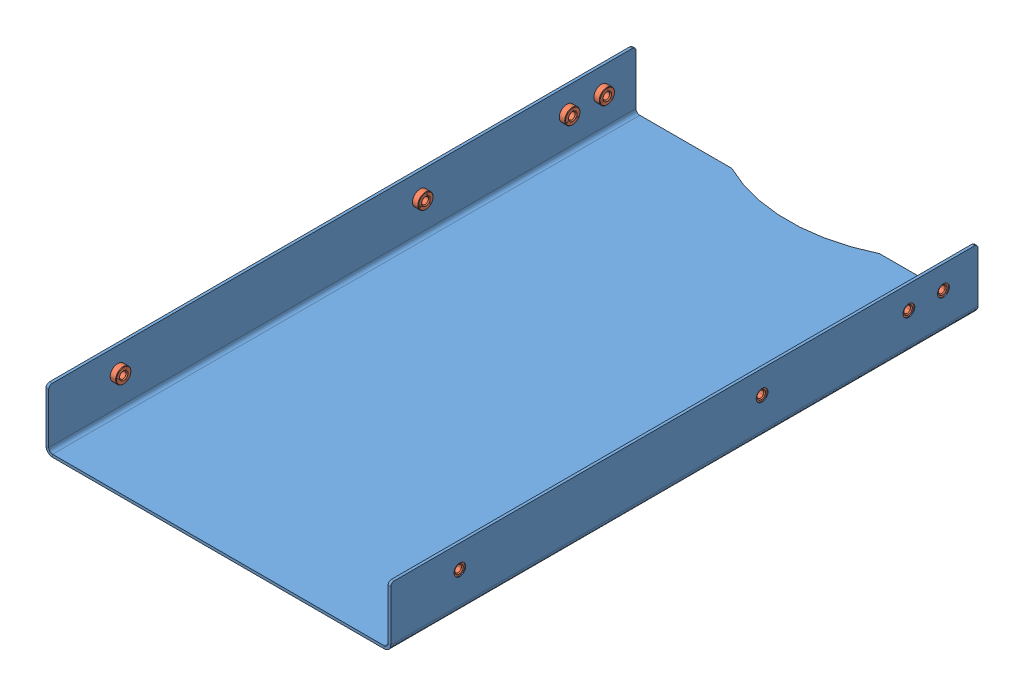
SolidWorks assembly GE-22334, configuration Default. Lengths in mm.
Overall size (253.49 44.45 431.8).
9 component instances, 2 part files, 22 mates.
Components (placement in the parent):
- GE-22334-01-1: GE-22334-01 [Default] at origin size (253.49 44.45 431.8)
- pem_clinchnut_.25_20_.054-1: pem_clinchnut_.25_20_.054 [Default] at (0.6223 25.4 -50.8) size (5.69 11.18 11.18)
- pem_clinchnut_.25_20_.054-6: pem_clinchnut_.25_20_.054 [Default] at (0.6223 25.4 -406.4) x (1 0 0) z (0 -0.371154 0.928571) size (5.69 11.18 11.18)
- pem_clinchnut_.25_20_.054-8: pem_clinchnut_.25_20_.054 [Default] at (252.8697 25.4 -406.4) x (-1 0 0) z (0 -0.421154 -0.906989) size (5.69 11.18 11.18)
- pem_clinchnut_.25_20_.054-14: pem_clinchnut_.25_20_.054 [Default] at (252.8697 25.4 -50.8) x (-1 0 0) z (0 -0.305088 -0.952324) size (5.69 11.18 11.18)
- pem_clinchnut_.25_20_.054-16: pem_clinchnut_.25_20_.054 [Default] at (0.6223 25.4 -273.05) x (1 0 0) z (0 -0.313094 0.949722) size (5.69 11.18 11.18)
- pem_clinchnut_.25_20_.054-18: pem_clinchnut_.25_20_.054 [Default] at (0.6223 25.4 -381) x (1 0 0) z (0 -0.431476 0.902124) size (5.69 11.18 11.18)
- pem_clinchnut_.25_20_.054-20: pem_clinchnut_.25_20_.054 [Default] at (252.8697 25.4 -381) x (-1 0 0) z (0 -0.513686 -0.857978) size (5.69 11.18 11.18)
- pem_clinchnut_.25_20_.054-22: pem_clinchnut_.25_20_.054 [Default] at (252.8697 25.4 -273.05) x (-1 0 0) z (0 -0.559632 -0.828741) size (5.69 11.18 11.18)
Mates (geometry in assembly coordinates):
- Concentric1: concentric aligned: cylinder of GE-22334-01-1 through (0 25.4 -50.8) axis (-1 0 0) radius 4.3688; cylinder of pem_clinchnut_.25_20_.054-1 through (1.651 25.4 -50.8) axis (-1 0 0) radius 4.9721
- Coincident1: coincident anti-aligned: plane of GE-22334-01-1 through (1.9939 0 0) normal (1 0 0); plane of pem_clinchnut_.25_20_.054-1 through (1.9939 25.4 -48.006) normal (-1 0 0)
- Concentric2: concentric aligned: cylinder of lowChuteBackRoof_hybrid_mockV2-1 through (0 25.4 -139.7) axis (-1 0 0) radius 4.3688; cylinder of pem_clinchnut_.25_20_.054-2 through (1.5545 25.4 -139.7) axis (-1 0 0) radius 4.9721
- Coincident2: coincident anti-aligned: plane of GE-22334-01-1 through (1.9939 0 0) normal (1 0 0); plane of pem_clinchnut_.25_20_.054-2 through (1.8974 24.957 -136.9413) normal (-1 0 0)
- Concentric3: concentric aligned: cylinder of lowChuteBackRoof_hybrid_mockV2-1 through (0 25.4 -317.5) axis (-1 0 0) radius 4.3688; cylinder of pem_clinchnut_.25_20_.054-4 through (2.0193 25.4 -317.5) axis (-1 0 0) radius 4.9721
- Coincident3: coincident anti-aligned: plane of GE-22334-01-1 through (1.9939 0 0) normal (1 0 0); plane of pem_clinchnut_.25_20_.054-4 through (2.3622 24.6093 -314.8202) normal (-1 0 0)
- Concentric4: concentric aligned: cylinder of GE-22334-01-1 through (0 25.4 -406.4) axis (-1 0 0) radius 4.3688; cylinder of pem_clinchnut_.25_20_.054-6 through (1.651 25.4 -406.4) axis (-1 0 0) radius 4.9721
- Coincident4: coincident anti-aligned: plane of GE-22334-01-1 through (1.9939 0 0) normal (1 0 0); plane of pem_clinchnut_.25_20_.054-6 through (1.9939 24.363 -403.8056) normal (-1 0 0)
- Concentric5: concentric anti-aligned: cylinder of GE-22334-01-1 through (0 25.4 -406.4) axis (-1 0 0) radius 4.3688; cylinder of pem_clinchnut_.25_20_.054-8 through (251.841 25.4 -406.4) axis (1 0 0) radius 4.9721
- Coincident5: coincident anti-aligned: plane of GE-22334-01-1 through (251.4981 0 0) normal (-1 0 0); plane of pem_clinchnut_.25_20_.054-8 through (251.4981 24.2233 -408.9341) normal (1 0 0)
- Concentric7: concentric anti-aligned: cylinder of lowChuteBackRoof_hybrid_mockV2-1 through (0 25.4 -139.7) axis (-1 0 0) radius 4.3688; cylinder of pem_clinchnut_.25_20_.054-12 through (251.9375 25.4 -139.7) axis (1 0 0) radius 4.9721
- Coincident7: coincident anti-aligned: plane of GE-22334-01-1 through (251.4981 0 0) normal (-1 0 0); plane of pem_clinchnut_.25_20_.054-12 through (251.5946 24.3025 -142.2694) normal (1 0 0)
- Concentric8: concentric anti-aligned: cylinder of GE-22334-01-1 through (0 25.4 -50.8) axis (-1 0 0) radius 4.3688; cylinder of pem_clinchnut_.25_20_.054-14 through (251.841 25.4 -50.8) axis (1 0 0) radius 4.9721
- Coincident8: coincident anti-aligned: plane of GE-22334-01-1 through (251.4981 0 0) normal (-1 0 0); plane of pem_clinchnut_.25_20_.054-14 through (251.4981 24.5476 -53.4608) normal (1 0 0)
- Concentric9: concentric aligned: cylinder of GE-22334-01-1 through (0 25.4 -273.05) axis (-1 0 0) radius 4.3688; cylinder of pem_clinchnut_.25_20_.054-16 through (1.651 25.4 -273.05) axis (-1 0 0) radius 4.9721
- Coincident9: coincident anti-aligned: plane of GE-22334-01-1 through (1.9939 0 0) normal (1 0 0); plane of pem_clinchnut_.25_20_.054-16 through (1.9939 24.5252 -270.3965) normal (-1 0 0)
- Concentric10: concentric aligned: cylinder of GE-22334-01-1 through (0 25.4 -381) axis (-1 0 0) radius 4.3688; cylinder of pem_clinchnut_.25_20_.054-18 through (1.651 25.4 -381) axis (-1 0 0) radius 4.9721
- Coincident10: coincident anti-aligned: plane of GE-22334-01-1 through (1.9939 0 0) normal (1 0 0); plane of pem_clinchnut_.25_20_.054-18 through (1.9939 24.1945 -378.4795) normal (-1 0 0)
- Concentric11: concentric anti-aligned: cylinder of GE-22334-01-1 through (0 25.4 -381) axis (-1 0 0) radius 4.3688; cylinder of pem_clinchnut_.25_20_.054-20 through (251.841 25.4 -381) axis (1 0 0) radius 4.9721
- Coincident11: coincident anti-aligned: plane of GE-22334-01-1 through (251.4981 0 0) normal (-1 0 0); plane of pem_clinchnut_.25_20_.054-20 through (251.4981 23.9648 -383.3972) normal (1 0 0)
- Concentric12: concentric anti-aligned: cylinder of GE-22334-01-1 through (0 25.4 -273.05) axis (-1 0 0) radius 4.3688; cylinder of pem_clinchnut_.25_20_.054-22 through (251.841 25.4 -273.05) axis (1 0 0) radius 4.9721
- Coincident12: coincident anti-aligned: plane of GE-22334-01-1 through (251.4981 0 0) normal (-1 0 0); plane of pem_clinchnut_.25_20_.054-22 through (251.4981 23.8364 -275.3655) normal (1 0 0)
